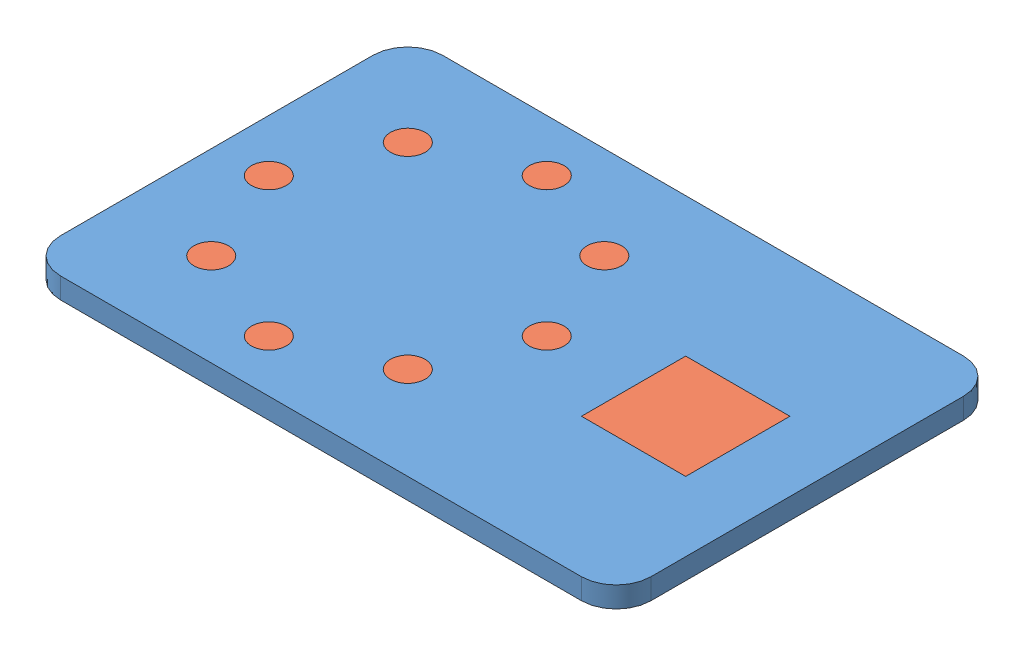
SolidWorks assembly Credit Card Full, configuration Default. Lengths in mm.
Overall size (85 3 55).
2 component instances, 2 part files, 3 mates.
Components (placement in the parent):
- Credit Card Thin Part 1-1: Credit Card Thin Part 1 [Default] at (36.9627 37.3458 66.3036) size (85 3 55)
- Credit Card Thin Part 2-1: Credit Card Thin Part 2 [Default] at (36.9627 37.3458 66.7368) size (70 3 45)
Mates (geometry in assembly coordinates):
- Coincident1: coincident anti-aligned: plane of Credit Card Thin Part 1-1 through (69.4627 40.3458 74.2368) normal (-1 0 0); plane of Credit Card Thin Part 2-1 through (69.4627 40.3458 66.7368) normal (1 0 0)
- Coincident2: coincident anti-aligned: plane of Credit Card Thin Part 1-1 through (69.4627 40.3458 74.2368) normal (0 0 -1); plane of Credit Card Thin Part 2-1 through (36.9627 40.3458 74.2368) normal (0 0 1)
- Coincident3: coincident aligned: plane of Credit Card Thin Part 1-1 through (36.9627 37.3458 66.3036) normal (0 -1 0); plane of Credit Card Thin Part 2-1 through (36.9627 37.3458 66.7368) normal (0 -1 0)
